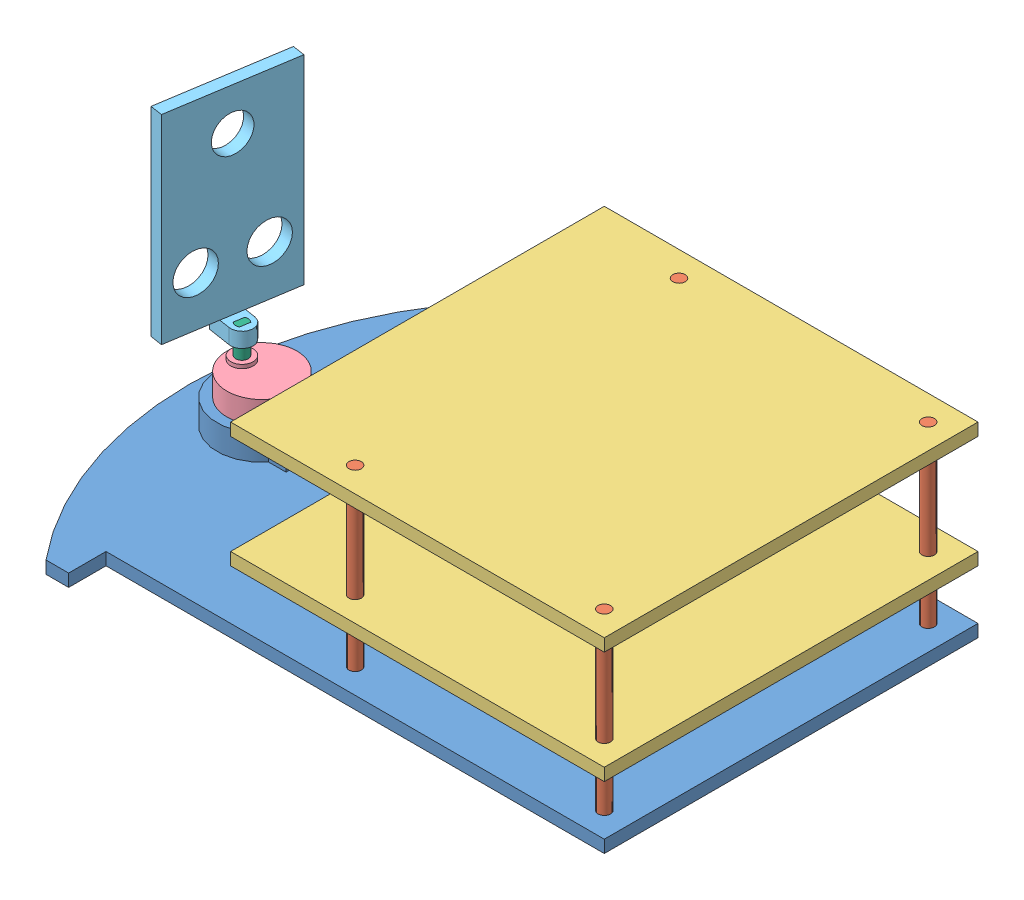
SolidWorks assembly carro, configuration Predeterminado. Lengths in mm.
Overall size (241.42 117 180).
10 component instances, 6 part files, 22 mates.
Components (placement in the parent):
- base-1: base [Predeterminado] at (-41.7619 -18.8297 241.4214) size (241.42 15 180)
- palo-1: palo [Predeterminado] at (-22.9773 -18.8297 186.8158) size (5 75 5)
- piso2-1: piso2 [Predeterminado] at (19.7916 51.1703 209.36) size (150 5 150)
- palo-2: palo [Predeterminado] at (77.0227 -18.8297 186.8158) size (5 75 5)
- palo-3: palo [Predeterminado] at (-22.9773 -18.8297 316.8158) size (5 75 5)
- palo-4: palo [Predeterminado] at (77.0227 -18.8297 316.8158) size (5 75 5)
- motor-1: motor [Predeterminado] at (-125.3986 -13.8297 251.8158) size (31 20.5 28)
- piso2-3: piso2 [Predeterminado] at (19.7916 6.1703 209.36) size (150 5 150)
- soporte-1: soporte [Predeterminado] at (-133.3986 12.1703 251.8158) x (0.98791 0 0.155031) z (-0.155031 0 0.98791) size (14 86 50)
- palomotor-1: palomotor [Predeterminado] at (-125.4954 -10.8297 253.0561) x (0.98791 0 0.155031) z (-0.155031 0 0.98791) size (5 13.5 5)
Mates (geometry in assembly coordinates):
- Coincidente1: coincident aligned: plane of palo-1 through (-22.9773 56.1703 186.8158) normal (0 1 0); plane of piso2-1 through (19.7916 56.1703 209.36) normal (0 1 0)
- Concéntrica1: concentric aligned: cylinder of palo-1 through (-22.9773 56.1703 186.8158) axis (0 -1 0) radius 2.5; cylinder of piso2-1 through (-22.9773 56.1703 186.8158) axis (0 -1 0) radius 2.5
- Coincidente3: coincident aligned: plane of piso2-1 through (19.7916 56.1703 209.36) normal (0 1 0); plane of palo-2 through (77.0227 56.1703 186.8158) normal (0 1 0)
- Concéntrica2: concentric aligned: cylinder of piso2-1 through (77.0227 56.1703 186.8158) axis (0 -1 0) radius 2.5; cylinder of palo-2 through (77.0227 56.1703 186.8158) axis (0 -1 0) radius 2.5
- Coincidente4: coincident aligned: plane of piso2-1 through (19.7916 56.1703 209.36) normal (0 1 0); plane of palo-3 through (-22.9773 56.1703 316.8158) normal (0 1 0)
- Concéntrica3: concentric aligned: cylinder of piso2-1 through (-22.9773 56.1703 316.8158) axis (0 -1 0) radius 2.5; cylinder of palo-3 through (-22.9773 56.1703 316.8158) axis (0 -1 0) radius 2.5
- Coincidente5: coincident aligned: plane of piso2-1 through (19.7916 56.1703 209.36) normal (0 1 0); plane of palo-4 through (77.0227 56.1703 316.8158) normal (0 1 0)
- Concéntrica6: concentric aligned: cylinder of piso2-1 through (77.0227 56.1703 316.8158) axis (0 -1 0) radius 2.5; cylinder of palo-4 through (77.0227 56.1703 316.8158) axis (0 -1 0) radius 2.5
- Concéntrica7: concentric aligned: cylinder of base-1 through (77.0227 -13.8297 316.8158) axis (0 -1 0) radius 2.5; cylinder of palo-4 through (77.0227 56.1703 316.8158) axis (0 -1 0) radius 2.5
- Concéntrica8: concentric aligned: cylinder of base-1 through (77.0227 -13.8297 186.8158) axis (0 -1 0) radius 2.5; cylinder of palo-2 through (77.0227 56.1703 186.8158) axis (0 -1 0) radius 2.5
- Coincidente6: coincident aligned: plane of base-1 through (-41.7619 -18.8297 241.4214) normal (0 -1 0); plane of palo-2 through (77.0227 -18.8297 186.8158) normal (0 -1 0)
- Coincidente7: coincident anti-aligned: plane of base-1 through (-41.7619 -13.8297 241.4214) normal (0 1 0); plane of motor-1 through (-125.3986 -13.8297 251.8158) normal (0 -1 0)
- Coincidente8: coincident anti-aligned: plane of base-1 through (-108.3986 -3.8297 241.4214) normal (-1 0 0); plane of motor-1 through (-108.3986 5.1703 251.8158) normal (1 0 0)
- Concéntrica9: concentric aligned: cylinder of base-1 through (-125.3986 -3.8297 251.8158) axis (0 -1 0) radius 14; cylinder of motor-1 through (-125.3986 5.1703 251.8158) axis (0 -1 0) radius 14
- Coincidente9: coincident aligned: plane of base-1 through (-41.7619 -13.8297 326.8158) normal (0 0 1); plane of piso2-3 through (19.7916 11.1703 326.8158) normal (0 0 1)
- Coincidente10: coincident aligned: plane of base-1 through (87.0227 -13.8297 241.4214) normal (1 0 0); plane of piso2-3 through (87.0227 11.1703 209.36) normal (1 0 0)
- Distancia1: distance = 20 mm anti-aligned: plane of piso2-3 through (19.7916 6.1703 209.36) normal (0 -1 0); plane of base-1 through (-41.7619 -13.8297 241.4214) normal (0 1 0)
- Coincidente15: coincident anti-aligned: plane of motor-1 through (-133.3986 4.6703 251.8158) normal (0 1 0); plane of palomotor-1 through (-133.3986 4.6703 251.8158) normal (0 -1 0)
- Concéntrica11: concentric aligned: cylinder of motor-1 through (-133.3986 16.6703 251.8158) axis (0 -1 0) radius 2.5; cylinder of palomotor-1 through (-133.3986 12.1703 251.8158) axis (0 -1 0) radius 2.5
- Coincidente16: coincident aligned: plane of soporte-1 through (-133.3986 18.1703 251.8158) normal (0 1 0); plane of palomotor-1 through (-125.4954 18.1703 253.0561) normal (0 1 0)
- Concéntrica12: concentric aligned: cylinder of soporte-1 through (-133.3986 18.1703 251.8158) axis (0 -1 0) radius 2.5; cylinder of palomotor-1 through (-133.3986 12.1703 251.8158) axis (0 -1 0) radius 2.5
- Coincidente17: coincident anti-aligned: plane of soporte-1 through (-134.8805 18.1703 251.5833) normal (0.98791 0 0.155031); plane of palomotor-1 through (-134.8805 18.1703 251.5833) normal (-0.98791 0 -0.155031)
